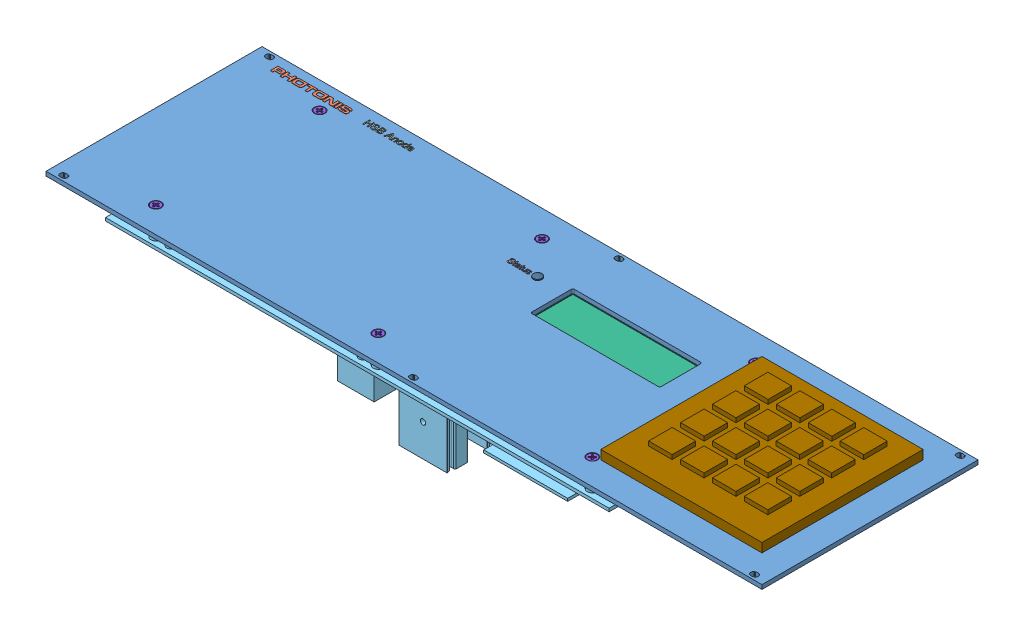
SolidWorks assembly MLA-0387-M5, configuration Default. Lengths in mm.
Overall size (426.52 63.69 128.7).
25 component instances, 13 part files, 41 mates.
Components (placement in the parent):
- MLA-0387-M10-1: MLA-0387-M10 [Default] at (-31.2027 -157.9839 598.0559) size (426.52 2.65 128.7)
  - MLA-0387-M1-1: MLA-0387-M1 [Default] at (-7.8975 -174.6729 597.0963) size (426.52 2.5 128.7)
  - LOGO PHOTONIS-1: LOGO PHOTONIS [Default] at (9.7425 205.5771 259.7963) x (1 0 0) z (0 1 0) size (45.16 4.45 0.15)
  - Anode text-1: Anode text [Default] at (64.2855 205.4271 259.8791) size (28.26 0.1 4.1)
  - Status text-1: Status text [Default] at (178.1079 205.4271 288.0463) size (13.33 0.1 3.59)
- MLA-0387-P1-PB1-3: MLA-0387-P1-PB1 [Default] at (-11.3802 30.9332 966.1522) x (1 0 0) z (0 1 0) size (300 107.5 53.19)
- NHD-0420D3Z-FL-GBW-V3-1: NHD-0420D3Z-FL-GBW-V3 [Default] at (170.3699 33.9432 922.6522) x (1 0 0) z (0 1 0) size (98 60 10.6)
- pan_head_phillip_M2x4-1: pan_head_phillip_M2x4 [Default] at (172.8699 35.5432 865.1522) x (1 0 0) z (0 0 1) size (4 9.78 4)
- pan_head_phillip_M2x4-2: pan_head_phillip_M2x4 [Default] at (265.8699 35.5432 865.1522) x (1 0 0) z (0 0 1) size (4 9.78 4)
- pan_head_phillip_M2x4-3: pan_head_phillip_M2x4 [Default] at (265.8699 35.5432 920.1522) x (1 0 0) z (0 0 1) size (4 9.78 4)
- pan_head_phillip_M2x4-4: pan_head_phillip_M2x4 [Default] at (172.8699 35.5432 920.1522) x (1 0 0) z (0 0 1) size (4 9.78 4)
- SCREW_ISO 7046-1: SCREW_ISO 7046 [VIJAK M 3x 10] at (13.6199 47.4432 863.6522) x (0 -1 0) z (0 0 1) size (10 5.6 5.6)
- SCREW_ISO 7046-2: SCREW_ISO 7046 [VIJAK M 3x 10] at (13.6199 47.4432 961.1522) x (0 -1 0) z (1 0 0) size (10 5.6 5.6)
- SCREW_ISO 7046-3: SCREW_ISO 7046 [VIJAK M 3x 10] at (146.1199 47.4432 961.1522) x (0 -1 0) z (0 0 1) size (10 5.6 5.6)
- SCREW_ISO 7046-4: SCREW_ISO 7046 [VIJAK M 3x 10] at (146.1199 47.4432 863.6522) x (0 -1 0) z (0 0 1) size (10 5.6 5.6)
- SCREW_ISO 7046-5: SCREW_ISO 7046 [VIJAK M 3x 10] at (273.6199 47.4432 863.6522) x (0 -1 0) z (0 0 1) size (10 5.6 5.6)
- SCREW_ISO 7046-6: SCREW_ISO 7046 [VIJAK M 3x 10] at (273.6199 47.3028 961.1522) x (0 -1 0) z (-0.743067 0 0.669217) size (10 5.6 5.6)
- Storm_7016010-2: Storm_7016010 [Default] at (277.7099 47.4432 960.2022) x (1 0 0) z (0 1 0) size (96 96 22)
- PLW5-500-1: PLW5-500 [Default] at (164.6199 47.4432 884.7422) size (5.25 13.97 5.07)
- MLA-0387-M7-1: MLA-0387-M7 [Default] at (17.6197 38.9432 966.1523) x (1 0 0) z (0 0 1) size (124.5 3 107.5)
- M2_5x8_Pan_head-1: M2_5x8_Pan_head [Default] at (22.6197 41.9432 863.6523) x (0 -1 0) z (-0.546944 0 0.837169) size (13.3 7.99 5.14)
- M2_5x8_Pan_head-2: M2_5x8_Pan_head [Default] at (22.6197 41.9432 961.1523) x (0 -1 0) z (-0.546944 0 0.837169) size (13.3 7.99 5.14)
- M2_5x8_Pan_head-3: M2_5x8_Pan_head [Default] at (137.1197 41.9432 863.6523) x (0 -1 0) z (-0.546944 0 0.837169) size (13.3 7.99 5.14)
- M2_5x8_Pan_head-4: M2_5x8_Pan_head [Default] at (137.1197 41.9432 961.1523) x (0 -1 0) z (-0.546944 0 0.837169) size (13.3 7.99 5.14)
- MLA-0387-C0-1: MLA-0387-C0 [Default] at (-5.7755 54.3236 1000.0477)
Mates (geometry in assembly coordinates):
- Concentric30: concentric aligned: cone of MLA-0387-M10-1/MLA-0387-M1-1 through (13.6199 47.4432 863.6522) axis (0 -1 0); cone of SCREW_ISO 7046-1 through (13.6199 45.9432 863.6522) axis (0 -1 0)
- Coincident48: coincident aligned: plane of MLA-0387-M10-1/MLA-0387-M1-1 through (-31.0198 47.4432 892.0763) normal (0 1 0); plane of SCREW_ISO 7046-1 through (13.6199 47.4432 863.6522) normal (0 1 0)
- Concentric31: concentric aligned: cone of MLA-0387-M10-1/MLA-0387-M1-1 through (13.6199 47.4432 961.1522) axis (0 -1 0); cone of SCREW_ISO 7046-2 through (13.6199 45.9432 961.1522) axis (0 -1 0)
- Coincident49: coincident aligned: plane of MLA-0387-M10-1/MLA-0387-M1-1 through (-31.0198 47.4432 892.0763) normal (0 1 0); plane of SCREW_ISO 7046-2 through (13.6199 47.4432 961.1522) normal (0 1 0)
- Concentric32: concentric aligned: cone of MLA-0387-M10-1/MLA-0387-M1-1 through (146.1199 47.4432 961.1522) axis (0 -1 0); cone of SCREW_ISO 7046-3 through (146.1199 45.9432 961.1522) axis (0 -1 0)
- Coincident50: coincident aligned: plane of MLA-0387-M10-1/MLA-0387-M1-1 through (-31.0198 47.4432 892.0763) normal (0 1 0); plane of SCREW_ISO 7046-3 through (146.1199 47.4432 961.1522) normal (0 1 0)
- Concentric33: concentric aligned: cone of MLA-0387-M10-1/MLA-0387-M1-1 through (146.1199 47.4432 863.6522) axis (0 -1 0); cone of SCREW_ISO 7046-4 through (146.1199 45.9432 863.6522) axis (0 -1 0)
- Coincident51: coincident aligned: plane of MLA-0387-M10-1/MLA-0387-M1-1 through (-31.0198 47.4432 892.0763) normal (0 1 0); plane of SCREW_ISO 7046-4 through (146.1199 47.4432 863.6522) normal (0 1 0)
- Concentric34: concentric aligned: cone of MLA-0387-M10-1/MLA-0387-M1-1 through (273.6199 47.4432 863.6522) axis (0 -1 0); cone of SCREW_ISO 7046-5 through (273.6199 45.9432 863.6522) axis (0 -1 0)
- Coincident52: coincident aligned: plane of MLA-0387-M10-1/MLA-0387-M1-1 through (-31.0198 47.4432 892.0763) normal (0 1 0); plane of SCREW_ISO 7046-5 through (273.6199 47.4432 863.6522) normal (0 1 0)
- Coincident53: coincident: circle of MLA-0387-M10-1/MLA-0387-M1-1; cone of SCREW_ISO 7046-6 through (273.6199 45.8028 961.1522) axis (0 -1 0)
- Concentric36: concentric aligned: cylinder of MLA-0387-M10-1/MLA-0387-M1-1 through (146.1199 47.4432 863.6522) axis (0 -1 0) radius 1.75; cylinder of MLA-0387-P1-PB1-3 through (146.1198 38.5432 863.6522) axis (0 -1 0) radius 3
- Concentric37: concentric aligned: circle of MLA-0387-M10-1/MLA-0387-M1-1; circle of MLA-0387-P1-PB1-3
- Coincident55: coincident anti-aligned: plane of MLA-0387-M10-1/MLA-0387-M1-1 through (-31.0198 44.9432 892.0763) normal (0 -1 0); plane of MLA-0387-P1-PB1-3 through (146.1198 44.9432 863.6522) normal (0 1 0)
- Concentric38: concentric aligned: cylinder of MLA-0387-P1-PB1-3 through (172.8699 29.5432 865.1522) axis (0 1 0) radius 2.175; cylinder of NHD-0420D3Z-FL-GBW-V3-1 through (172.8699 33.9432 865.1522) axis (0 1 0) radius 1.25
- Coincident57: coincident aligned: circle of MLA-0387-P1-PB1-3; plane of NHD-0420D3Z-FL-GBW-V3-1 through (170.3699 33.9432 922.6522) normal (0 -1 0)
- Concentric40: concentric aligned: cylinder of MLA-0387-P1-PB1-3 through (265.8699 29.5432 865.1522) axis (0 1 0) radius 2.175; cylinder of NHD-0420D3Z-FL-GBW-V3-1 through (265.8699 33.9432 865.1522) axis (0 1 0) radius 1.25
- Concentric41: concentric anti-aligned: cylinder of MLA-0387-P1-PB1-3 through (172.8699 29.5432 865.1522) axis (0 1 0) radius 2.175; cylinder of pan_head_phillip_M2x4-1 through (172.8699 37.3282 865.1522) axis (0 -1 0) radius 2
- Coincident58: coincident anti-aligned: plane of NHD-0420D3Z-FL-GBW-V3-1 through (170.3699 35.5432 922.6522) normal (0 1 0); plane of pan_head_phillip_M2x4-1 through (172.8699 35.5432 865.1522) normal (0 -1 0)
- Concentric42: concentric anti-aligned: cylinder of MLA-0387-P1-PB1-3 through (265.8699 29.5432 865.1522) axis (0 1 0) radius 2.175; cylinder of pan_head_phillip_M2x4-2 through (265.8699 37.3282 865.1522) axis (0 -1 0) radius 2
- Coincident59: coincident anti-aligned: plane of NHD-0420D3Z-FL-GBW-V3-1 through (170.3699 35.5432 922.6522) normal (0 1 0); plane of pan_head_phillip_M2x4-2 through (265.8699 35.5432 865.1522) normal (0 -1 0)
- Concentric43: concentric anti-aligned: cylinder of MLA-0387-P1-PB1-3 through (265.8699 29.5432 920.1522) axis (0 1 0) radius 2.175; cylinder of pan_head_phillip_M2x4-3 through (265.8699 37.3282 920.1522) axis (0 -1 0) radius 2
- Coincident60: coincident anti-aligned: plane of NHD-0420D3Z-FL-GBW-V3-1 through (170.3699 35.5432 922.6522) normal (0 1 0); plane of pan_head_phillip_M2x4-3 through (265.8699 35.5432 920.1522) normal (0 -1 0)
- Concentric44: concentric anti-aligned: cylinder of MLA-0387-P1-PB1-3 through (172.8699 29.5432 920.1522) axis (0 1 0) radius 2.175; cylinder of pan_head_phillip_M2x4-4 through (172.8699 37.3282 920.1522) axis (0 -1 0) radius 2
- Coincident61: coincident anti-aligned: plane of NHD-0420D3Z-FL-GBW-V3-1 through (170.3699 35.5432 922.6522) normal (0 1 0); plane of pan_head_phillip_M2x4-4 through (172.8699 35.5432 920.1522) normal (0 -1 0)
- Concentric45: concentric anti-aligned: cylinder of MLA-0387-M10-1/MLA-0387-M1-1 through (293.7099 47.4432 880.2022) axis (0 -1 0) radius 1.75; cylinder of Storm_7016010-2 through (293.7099 33.4432 880.2022) axis (0 1 0) radius 1.5
- Concentric46: concentric anti-aligned: cylinder of MLA-0387-M10-1/MLA-0387-M1-1 through (357.7099 47.4432 944.2022) axis (0 -1 0) radius 1.75; cylinder of Storm_7016010-2 through (357.7099 33.4432 944.2022) axis (0 1 0) radius 1.5
- Coincident62: coincident anti-aligned: plane of MLA-0387-M10-1/MLA-0387-M1-1 through (-31.0198 47.4432 892.0763) normal (0 1 0); plane of Storm_7016010-2 through (277.7099 47.4432 960.2022) normal (0 -1 0)
- Coincident63: coincident anti-aligned: plane of MLA-0387-M10-1/MLA-0387-M1-1 through (-31.0198 47.4432 892.0763) normal (0 1 0); plane of PLW5-500-1 through (162.0879 47.4432 882.2102) normal (0 -1 0)
- Concentric47: concentric aligned: circle of MLA-0387-M10-1/MLA-0387-M1-1; cylinder of PLW5-500-1 through (164.6199 35.9288 884.7422) axis (0 1 0) radius 1.9304
- Concentric48: concentric anti-aligned: cylinder of MLA-0387-P1-PB1-3 through (22.6197 27.095 863.6523) axis (0 -1 0) radius 1.0065; cylinder of MLA-0387-M7-1 through (22.6197 38.9432 863.6523) axis (0 1 0) radius 1.5
- Concentric49: concentric anti-aligned: cylinder of MLA-0387-P1-PB1-3 through (137.1197 27.095 961.1523) axis (0 -1 0) radius 1.0065; cylinder of MLA-0387-M7-1 through (137.1197 38.9432 961.1523) axis (0 1 0) radius 1.5
- Coincident64: coincident anti-aligned: plane of MLA-0387-P1-PB1-3 through (139.6697 38.9432 961.1523) normal (0 1 0); plane of MLA-0387-M7-1 through (17.6197 38.9432 966.1523) normal (0 -1 0)
- Concentric50: concentric aligned: cylinder of MLA-0387-M7-1 through (22.6197 38.9432 863.6523) axis (0 1 0) radius 1.5; cylinder of M2_5x8_Pan_head-1 through (22.6197 36.5024 863.6523) axis (0 1 0) radius 1
- Coincident65: coincident anti-aligned: plane of MLA-0387-M7-1 through (17.6197 41.9432 966.1523) normal (0 1 0); plane of M2_5x8_Pan_head-1 through (23.6007 41.9432 862.1509) normal (0 -1 0)
- Concentric51: concentric aligned: cylinder of MLA-0387-M7-1 through (22.6197 38.9432 961.1523) axis (0 1 0) radius 1.5; cylinder of M2_5x8_Pan_head-2 through (22.6197 36.5024 961.1523) axis (0 1 0) radius 1
- Coincident66: coincident anti-aligned: plane of MLA-0387-M7-1 through (17.6197 41.9432 966.1523) normal (0 1 0); plane of M2_5x8_Pan_head-2 through (23.6007 41.9432 959.6509) normal (0 -1 0)
- Concentric52: concentric aligned: cylinder of MLA-0387-M7-1 through (137.1197 38.9432 863.6523) axis (0 1 0) radius 1.5; cylinder of M2_5x8_Pan_head-3 through (137.1197 36.5024 863.6523) axis (0 1 0) radius 1
- Coincident67: coincident anti-aligned: plane of MLA-0387-M7-1 through (17.6197 41.9432 966.1523) normal (0 1 0); plane of M2_5x8_Pan_head-3 through (138.1007 41.9432 862.1508) normal (0 -1 0)
- Concentric53: concentric aligned: cylinder of MLA-0387-M7-1 through (137.1197 38.9432 961.1523) axis (0 1 0) radius 1.5; cylinder of M2_5x8_Pan_head-4 through (137.1197 36.5024 961.1523) axis (0 1 0) radius 1
- Coincident68: coincident anti-aligned: plane of MLA-0387-M7-1 through (17.6197 41.9432 966.1523) normal (0 1 0); plane of M2_5x8_Pan_head-4 through (138.1007 41.9432 959.6508) normal (0 -1 0)
